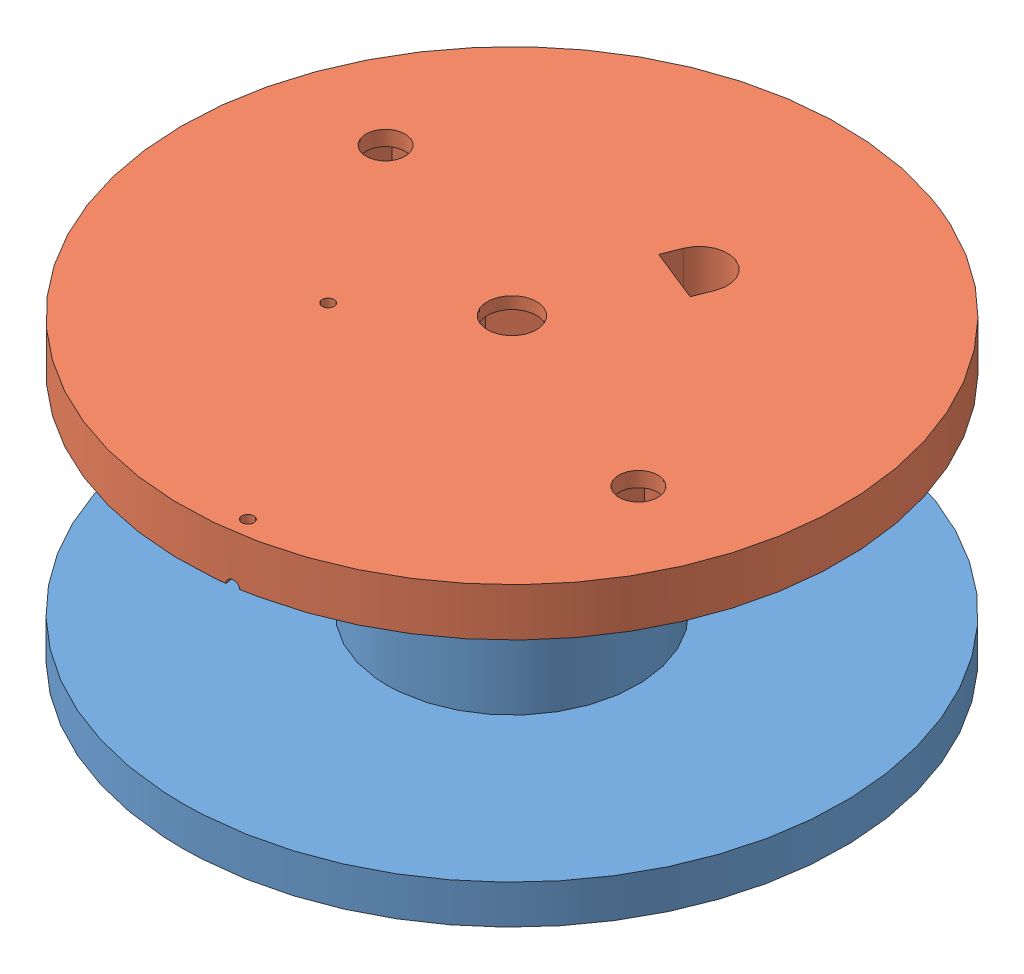
SolidWorks assembly Coil, configuration Default. Lengths in mm.
Overall size (71.51 24.75 71.51).
4 component instances, 4 part files, 5 mates.
Components (placement in the parent):
- Coil_Male-1: Coil_Male [Default] at (11.8723 9.9043 23.1823) size (55 16 55)
- Coil_Female-1: Coil_Female [Default] at (11.8723 34.6543 23.1823) x (0.928295 0 0.371844) z (0.371844 0 -0.928295) size (55 12.75 55)
- Coil_Winding-1: Coil_Winding [Default] at (11.8723 13.5543 23.1823) x (0.102713 0 -0.994711) z (0.994711 0 0.102713) size (19.45 17.5 19.45) (hidden)
- Core-1: Core [Default] at (11.8723 29.9043 23.1823) x (-0.545969 0 -0.837805) z (-0.837805 0 0.545969) size (12.85 20 12.85) (hidden)
Mates (geometry in assembly coordinates):
- Concentric3: concentric anti-aligned: cylinder of Coil_Male-1 through (11.8723 62.0596 23.1823) axis (0 -1 0) radius 8.275; cylinder of Coil_Female-1 through (11.8723 -16.332 23.1823) axis (0 1 0) radius 8.425
- LimitDistance1: limit distance = 0 mm anti-aligned: plane of Coil_Male-1 through (11.8723 21.9043 23.1823) normal (0 1 0); plane of Coil_Female-1 through (11.8723 21.9043 23.1823) normal (0 -1 0)
- Concentric4: concentric anti-aligned: cylinder of Coil_Male-1 through (11.8723 60.1407 23.1823) axis (0 -1 0) radius 10.425; circle of Coil_Winding-1
- Coincident1: coincident aligned: plane of Coil_Male-1 through (11.8723 13.1543 23.1823) normal (0 1 0); point of Coil_Winding-1
- Coincident3: coincident anti-aligned: circle of Coil_Male-1; circle of Core-1
